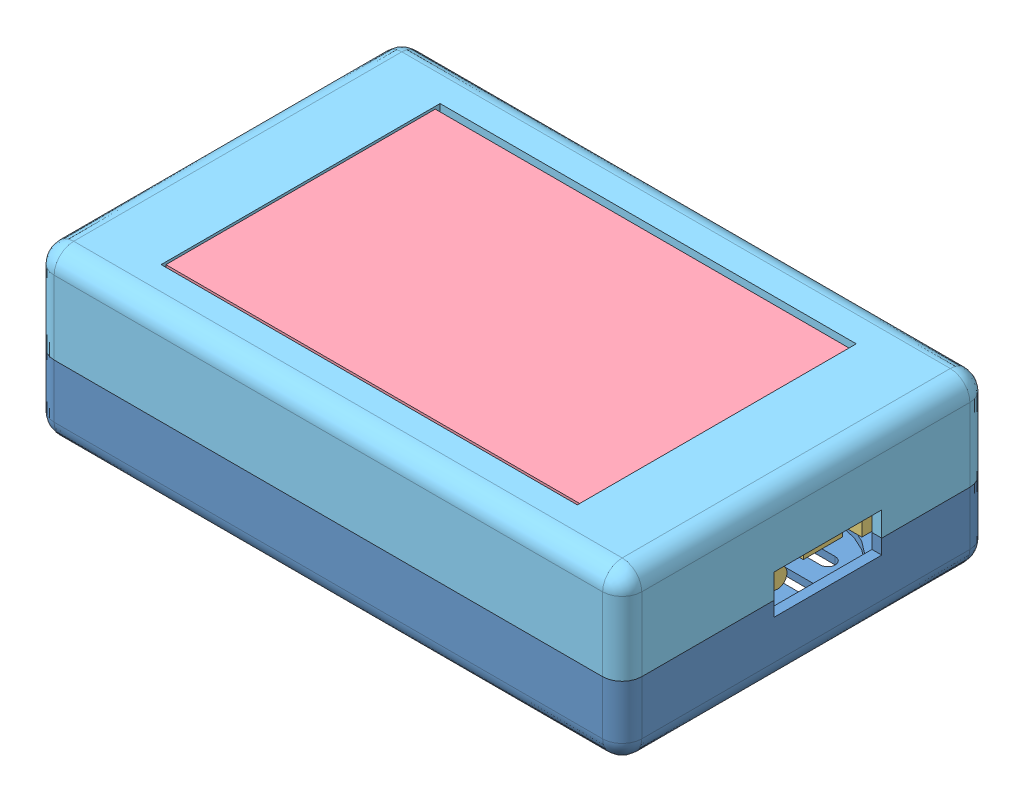
SolidWorks assembly typhone, configuration Default. Lengths in mm.
Overall size (120 34 75).
6 component instances, 6 part files, 14 mates.
Components (placement in the parent):
- typhone-bottom-1: typhone-bottom [Default] at (-3.6228 -17.7589 8.8815) size (120 16 75)
- piA+-1: piA+ [Default] at (-20.6228 -9.7589 8.8815) size (69.97 13 59.1)
- fona-1: fona [Default] at (34.0422 0.2411 -0.9335) x (0 0 1) z (1 0 0) size (44.45 10.5 33.65)
- pitft3.5-1: pitft3.5 [Default] at (-4.0778 10.2411 9.1015) size (97.09 20.5 56.64)
- typhone-top-1: typhone-top [Default] at (-3.6228 16.2411 8.8815) x (-1 0 0) z (0 0 1) size (120 19 75)
- picam-1: picam [Default] at (33.8772 -8.7589 29.6315) x (1 0 0) z (0 0 -1) size (25 8 23.5)
Mates (geometry in assembly coordinates):
- Coincident1: coincident anti-aligned: plane of typhone-bottom-1 through (8.3772 -9.7589 -15.6185) normal (0 1 0); plane of piA+-1 through (-20.6228 -9.7589 8.8815) normal (0 -1 0)
- Concentric2: concentric aligned: circle of typhone-bottom-1; circle of piA+-1
- Coincident3: coincident anti-aligned: plane of typhone-bottom-1 through (47.3772 -1.7589 -20.6185) normal (0 1 0); plane of fona-1 through (34.0422 -1.7589 -0.9335) normal (0 -1 0)
- Concentric5: concentric anti-aligned: circle of typhone-bottom-1; circle of fona-1
- Concentric6: concentric anti-aligned: circle of typhone-bottom-1; circle of fona-1
- Coincident4: coincident anti-aligned: plane of piA+-1 through (-20.6228 1.2411 8.8815) normal (0 1 0); plane of pitft3.5-1 through (-4.0778 1.2411 9.1015) normal (0 -1 0)
- Coincident5: coincident anti-aligned: plane of piA+-1 through (-45.6228 1.2411 -18.1185) normal (0 0 -1); plane of pitft3.5-1 through (-45.6228 1.2411 -18.1185) normal (0 0 1)
- Coincident6: coincident aligned: plane of piA+-1 through (-45.6228 1.2411 -18.1185) normal (-1 0 0); plane of pitft3.5-1 through (-45.6228 -4.7589 -13.0185) normal (-1 0 0)
- Coincident7: coincident anti-aligned: plane of typhone-bottom-1 through (-3.6228 -2.7589 8.8815) normal (0 1 0); plane of typhone-top-1 through (-3.6228 -2.7589 8.8815) normal (0 -1 0)
- Coincident8: coincident anti-aligned: line of typhone-bottom-1 through (52.3772 -2.7589 -28.6185) axis (-1 0 0); line of typhone-top-1 through (-59.6228 -2.7589 -28.6185) axis (1 0 0)
- Coincident9: coincident anti-aligned: line of typhone-bottom-1 through (-63.6228 -2.7589 -24.6185) axis (0 0 1); line of typhone-top-1 through (-63.6228 -2.7589 42.3815) axis (0 0 -1)
- Coincident10: coincident anti-aligned: plane of typhone-bottom-1 through (44.3772 -9.7589 39.3815) normal (0 1 0); plane of picam-1 through (33.8772 -9.7589 29.6315) normal (0 -1 0)
- Concentric7: concentric anti-aligned: circle of typhone-bottom-1; circle of picam-1
- Concentric8: concentric anti-aligned: circle of typhone-bottom-1; circle of picam-1
